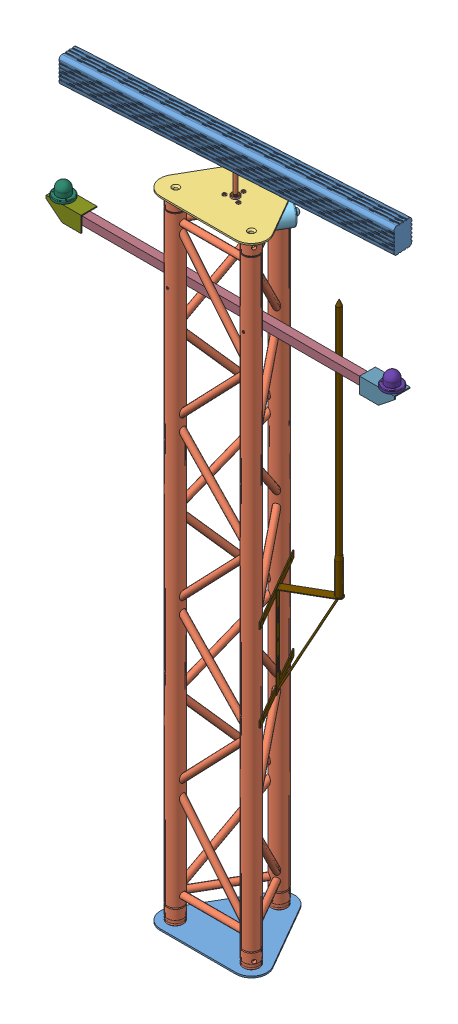
SolidWorks assembly ver2, configuration 默认. Lengths in mm.
Overall size (1100 2175.1 459.32).
26 component instances, 20 part files, 1 mates.
Components (placement in the parent):
- Mast_base-1: Mast_base [Default] at origin size (1100 2042.1 459.32)
  - F33Base-3: F33Base [Default] at origin size (337 45.53 304.98)
  - F33200-1: F33200 [Default] at (0 5 0) x (0.5 0 -0.866025) z (0.866025 0 0.5) size (290 2000 257.85)
  - F33Top-1: F33Top [Default] at (0 2010 0) x (-1 0 0) z (0 0 1) size (337 45.53 304.98)
  - PN01007-38-1: PN01007-38 [Default] at (76.4851 1974.3504 6.3178) x (0.5 0 -0.866025) z (0 -1 0) size (178.45 132.33 128.78)
    - Motor base-1: Motor base [Default] at (-152.2712 -0.4036 -6.25) size (83.57 110.11 82.51)
    - Case-1: Case [Default] at (-112.7712 36.1964 5.25) x (1 0 0) z (0 0.707107 0.707107) size (99 68 89.77)
    - Motor buttom plate-1: Motor buttom plate [Default] at (-152.2712 -0.4036 13.25) size (83.5 92.5 5)
    - Hexagon nut M6-1: Hexagon nut M6 [Default] at (-183.7712 36.1964 5.25) x (0 0.035119 0.999383) z (-1 0 0) size (10 11.55 5)
    - C type shaft ring-1: C type shaft ring [Default] at (-152.2712 -0.4036 -42.25) size (12.1 14.2 1)
    - Gasket-1: Gasket [Default] at (-152.2712 -0.4036 -42.25) size (20 20 1)
    - Screw M4 x 8-1: Screw M4 x 8 [Default] at (-107.8826 7.9121 -23.0343) x (-1 0 0) z (0 0.546829 0.837245) size (10.42 9.4 9.4)
    - Screw M4 x 8-2: Screw M4 x 8 [Default] at (-108.2565 64.4807 33.5343) x (-1 0 0) z (0 -0.949082 -0.315028) size (10.42 9.4 9.4)
    - Screw M3 x 8-1: Screw M3 x 8 [Default] at (-113.7712 -8.9036 21.2013) x (0 0 -1) z (0.920717 0.390231 0) size (10.35 5.6 5.6)
    - Screw M3 x 8-2: Screw M3 x 8 [Default] at (-152.2712 48.5964 20.3324) x (0 0 -1) z (0.328896 0.944366 0) size (10.35 5.6 5.6)
    - Screw M3 x 8-3: Screw M3 x 8 [Default] at (-186.2712 -20.4036 20.6964) x (0 0 -1) z (-0.774351 -0.632757 0) size (10.35 5.6 5.6)
    - Shaft-1: Shaft [Default] at (-152.2712 -0.4036 15.05) x (0 0 1) z (0.211595 -0.977357 0) size (82.8 67.2 67.2)
  - Navigation light tube-1: Navigation light tube [Default] at (0 1746.4934 182.8461) size (1000 25.4 25.4)
  - LED navigation light mount-1: LED navigation light mount [Default] at (440 1759.1934 185.8461) size (110 50 50)
  - LED navigation light red-3: LED navigation light red [Default] at (-519.5 1762.1934 162.3461) size (61 43.8 61)
  - MirrorLED navigation light mount-3: MirrorLED navigation light mount [Default] at (-440 1759.1934 185.8461) x (-1 0 0) z (0 0 -1) size (110 50 50)
  - LED navigation light green-1: LED navigation light green [Default] at (519.5 1762.1934 162.3461) size (61 43.8 61)
  - Whip antenna-1: Whip antenna [Default] at (81.6506 816.5 91.423) x (-0.5 0 -0.866025) z (0.866025 0 -0.5) size (290 1102.8 158.5)
- Mast_top-1: Mast_top [Default] at (38.2571 1716.81 105.6373) x (-0.998205 0 0.059892) z (-0.059892 0 -0.998205) size (1000 155.5 60)
  - Radar Antenna-1: Radar Antenna [Default] at (40.1259 378.2904 -30) size (1000 80 60)
  - Radar Antenna Rivot-1: Radar Antenna Rivot [Default] at (3037.9337 2325.2904 1074.3985) x (0 0 1) z (-1 0 0) size (35 75.5 240)
Mates (geometry in assembly coordinates):
- 铰链1: hinge anti-aligned: cylinder of Mast_base-1/PN01007-38-1/Shaft-1 through (0 2019.6004 137.9867) axis (0 1 0) radius 4.7625; cylinder of Mast_top-1/Radar Antenna Rivot-1 through (0 2002.6298 137.9867) axis (0 1 0) radius 6; plane of Mast_base-1/PN01007-38-1/Shaft-1 through (0.1051 2042.1004 146.1205) normal (0 1 0); plane of Mast_top-1/Radar Antenna Rivot-1 through (0 2042.1004 137.9867) normal (0 -1 0)
